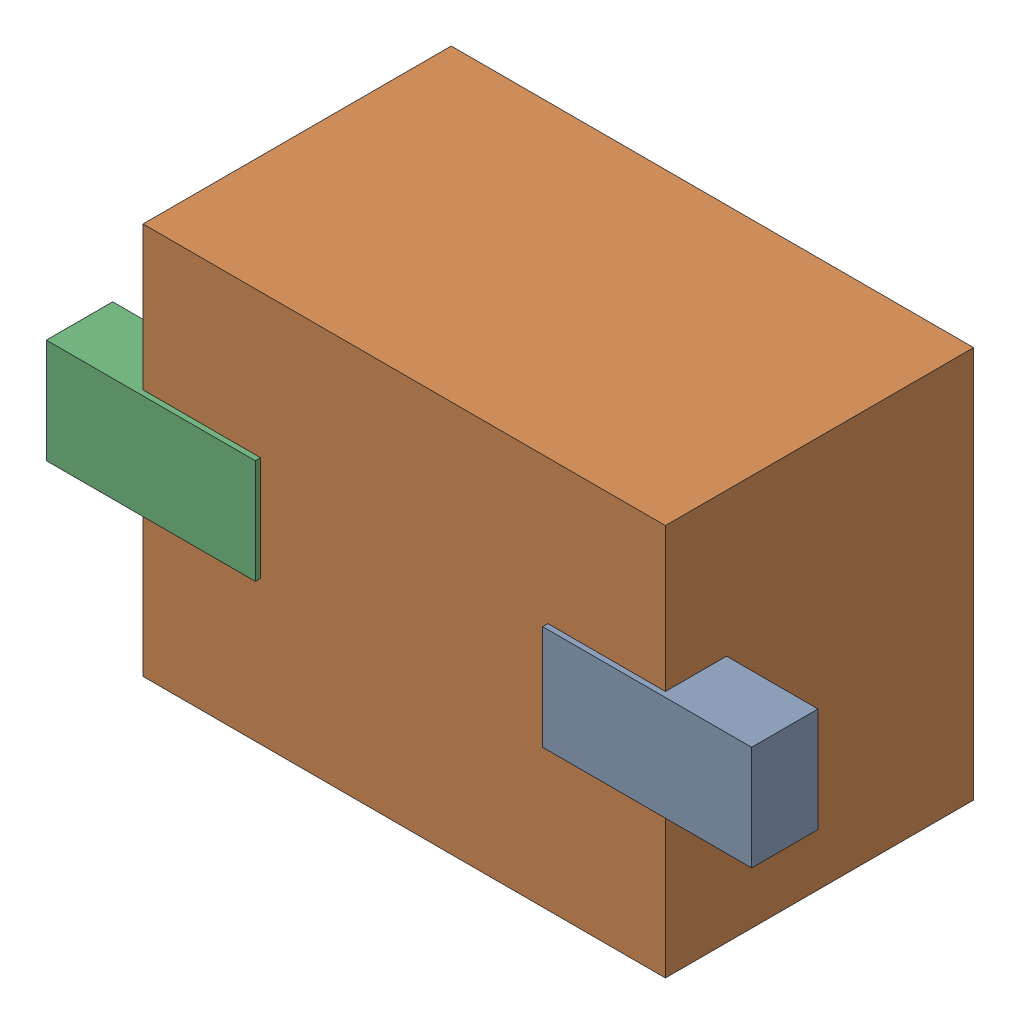
SolidWorks assembly D7, configuration Default. Lengths in mm.
Overall size (2.7 1.5 1.2).
6 component instances, 2 part files, 0 mates.
Components (placement in the parent):
- 710424080-1: 710424080 [Default] at (15.9 32.7 -0.6655) size (0.8 0.4 0.25)
  - Extruded (18)-1: Extruded (18) [Default] at origin size (0.8 0.4 0.25)
- 710423952-1: 710423952 [Default] at (14.95 32.7 -1.6115) size (2 1.5 1.18)
  - Extruded (19)-1: Extruded (19) [Default] at origin size (2 1.5 1.18)
- 710424080_1-1: 710424080_1 [Default] at (14 32.7 -0.6655) size (0.8 0.4 0.25)
  - Extruded (18)-1: Extruded (18) [Default] at origin size (0.8 0.4 0.25)
